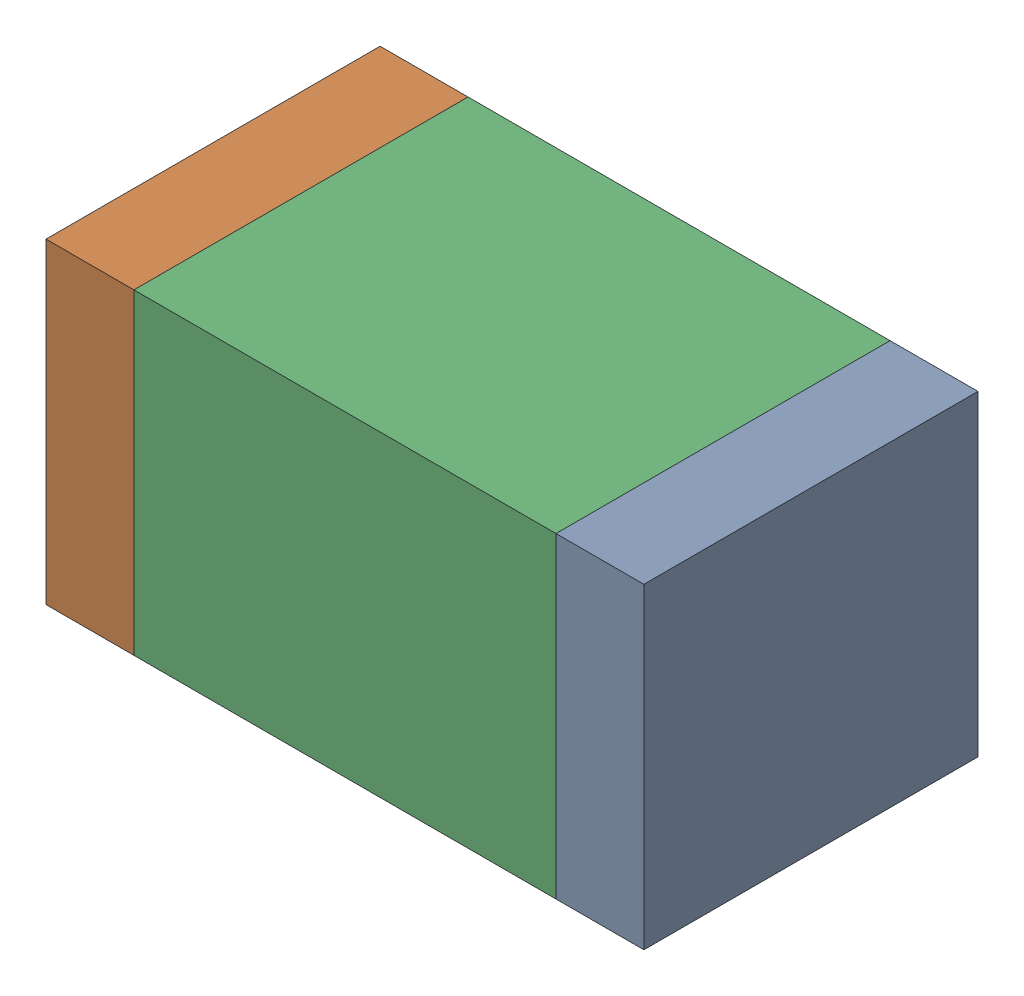
SolidWorks assembly C1-2, configuration Default. Lengths in mm.
Overall size (3.4 1.8 1.9).
6 component instances, 2 part files, 0 mates.
Components (placement in the parent):
- 959208392-2-1: 959208392-2 [Default] at (133.022 83.687 0) size (0.5 1.8 1.9)
  - Extruded-74-1: Extruded-74 [Default] at origin size (0.5 1.8 1.9)
- 959208392-2-2: 959208392-2 [Default] at (130.122 83.687 0) size (0.5 1.8 1.9)
  - Extruded-74-1: Extruded-74 [Default] at origin size (0.5 1.8 1.9)
- 959208256-2-1: 959208256-2 [Default] at (131.572 83.687 0) size (2.4 1.8 1.9)
  - Extruded-75-1: Extruded-75 [Default] at origin size (2.4 1.8 1.9)
